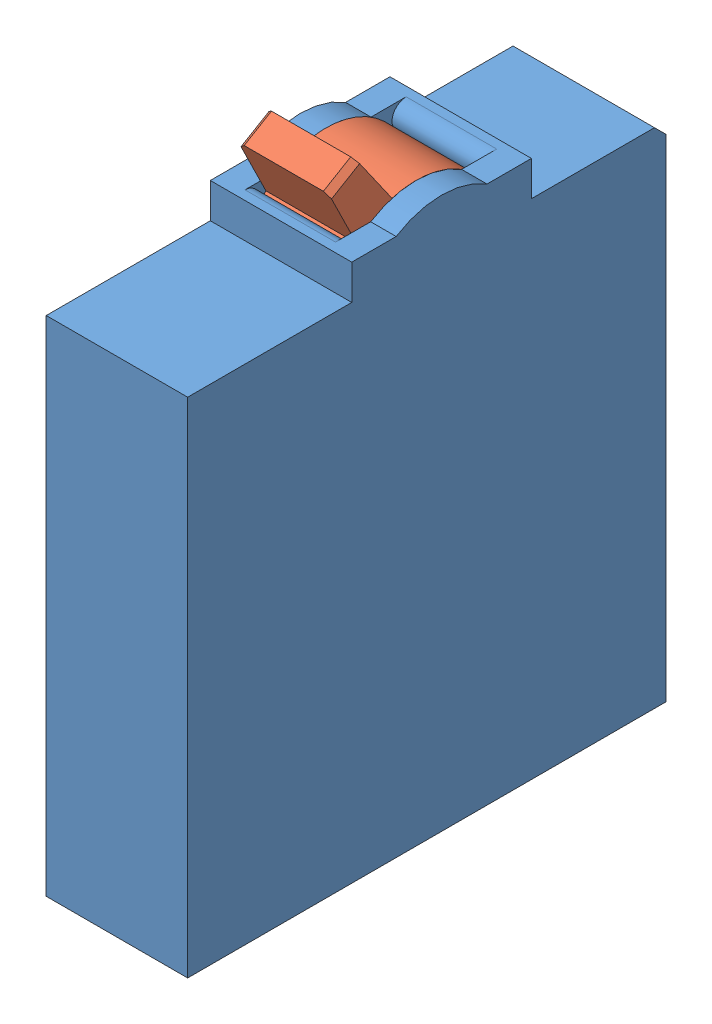
SolidWorks assembly M-P-003-Breaker Model, configuration Default. Lengths in mm.
Overall size (25 111.98 84.5).
2 component instances, 2 part files, 3 mates.
Components (placement in the parent):
- M-P-003-Breaker Model Base-1: M-P-003-Breaker Model Base [Default] at origin size (25 97.4 84.5)
- M-P-003-Breaker Model Switch-1: M-P-003-Breaker Model Switch [Default] at (4.5 -12.67 0) x (1 0 0) z (0 -0.508856 0.860852) size (16 40.5 30)
Mates (geometry in assembly coordinates):
- Concentric1: concentric anti-aligned: cylinder of M-P-003-Breaker Model Base-1 through (-42.4264 -12.67 0) axis (1 0 0) radius 15; cylinder of M-P-003-Breaker Model Switch-1 through (20.5 -12.67 0) axis (-1 0 0) radius 15
- Width1: width anti-aligned: plane of M-P-003-Breaker Model Switch-1 through (4.5 -12.67 0) normal (-1 0 0); plane of M-P-003-Breaker Model Base-1 through (20.5 -12.67 0) normal (1 0 0); plane of M-P-003-Breaker Model Switch-1 through (4.5 0 0) normal (1 0 0); plane of M-P-003-Breaker Model Base-1 through (20.5 -12.67 0) normal (-1 0 0)
- Angle2: planar angle = 2.181662 rad anti-aligned: plane of M-P-003-Breaker Model Switch-1 through (20.5 10.7091 10.5611) normal (0 0.573576 -0.819152); plane of M-P-003-Breaker Model Base-1 through (25 -6.17 -15.875) normal (0 1 0)
